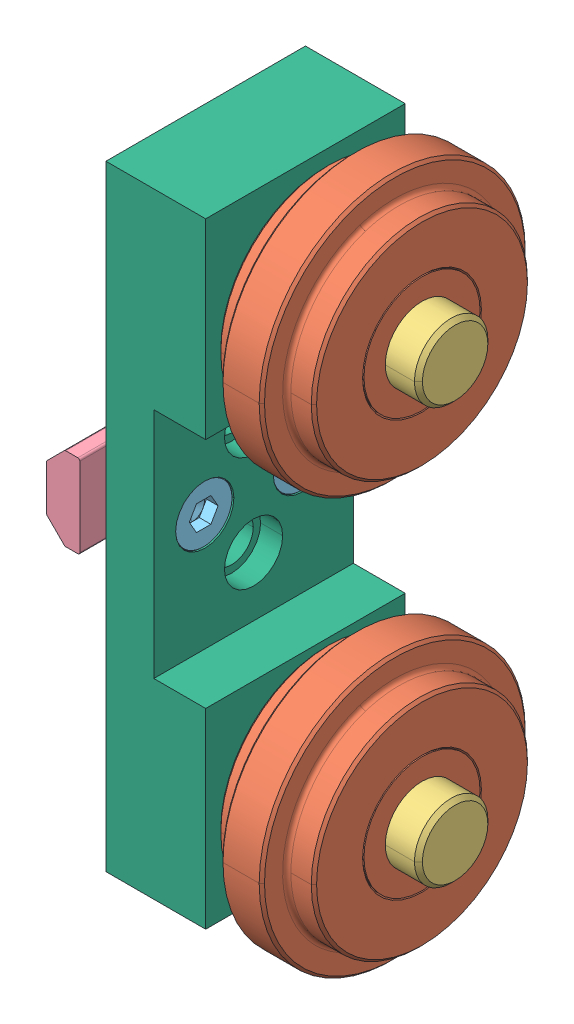
SolidWorks assembly 2755_1_wheelsSubassembly, configuration Default. Lengths in mm.
Overall size (58.57 130.18 50.8).
11 component instances, 6 part files, 0 mates.
Components (placement in the parent):
- 2755_1_3-1: 2755_1_3 [Default] at (20.6375 -39.6875 0) size (3.18 19.05 19.05)
- 2755_1_5-1: 2755_1_5 [Default] at (32.1564 -39.6875 0) size (18.29 50.8 50.8)
- 2755_1_7-1: 2755_1_7 [Default] at (41.3004 -39.6875 0) x (-1 0 0) z (0 0 1) size (38.1 14.02 14.02)
- 2755_1_3-2: 2755_1_3 [Default] at (20.6375 39.6875 0) size (3.18 19.05 19.05)
- 2755_1_5-2: 2755_1_5 [Default] at (32.1564 39.6875 0) size (18.29 50.8 50.8)
- 2755_1_7-2: 2755_1_7 [Default] at (41.3004 39.6875 0) x (-1 0 0) z (0 0 1) size (38.1 14.02 14.02)
- 2755_1_12-1: 2755_1_12 [Default] at (-10.414 0 -9.3218) x (0 -1 0) z (0 0 1) size (15.88 6.35 17.78)
- 2755_1_14-1: 2755_1_14 [Default] at (4.9276 0 -9.3218) x (-1 0 0) z (0 1 0) size (19.89 11.1 11.1)
- 2755_1_12-2: 2755_1_12 [Default] at (-10.414 0 9.3218) x (0 1 0) z (0 0 -1) size (15.88 6.35 17.78)
- 2755_1_14-2: 2755_1_14 [Default] at (4.9276 0 9.3218) x (-1 0 0) z (0 -1 0) size (19.89 11.1 11.1)
- 2755_1_18part-1: 2755_1_18part [Default] at (9.144 0 0) x (0 0 -1) z (1 0 0) size (38.1 117.48 19.05)
